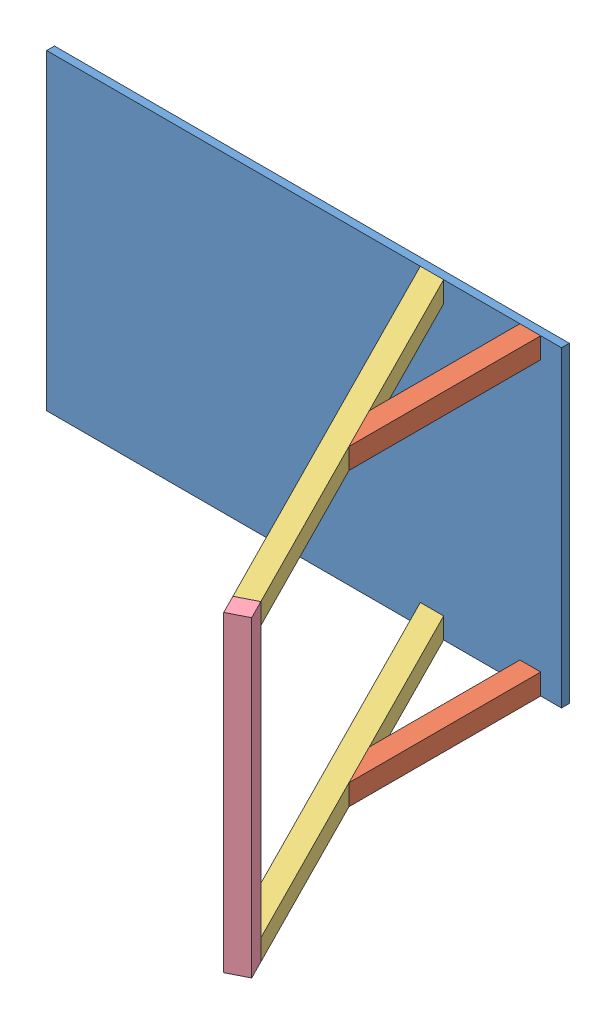
SolidWorks assembly Full_Assembly, configuration Default. Lengths in mm.
Overall size (6076.28 3048 4080.32).
6 component instances, 4 part files, 16 mates.
Components (placement in the parent):
- Boat_Deck-3: Boat_Deck [Default] at origin size (5029.2 3048 76.2)
- Vertical_Rod-1: Vertical_Rod [Default] at (4622.8 203.2 76.2) x (1 0 0) z (0 -1 0) size (203.2 1873.5 203.2)
- Vertical_Rod-2: Vertical_Rod [Default] at (4622.8 3048 76.2) x (1 0 0) z (0 -1 0) size (203.2 1873.5 203.2)
- Angled_Rod-2: Angled_Rod [Default] at (3649.8183 3048 76.2) x (0.451656 0 0.892192) z (0.892192 0 -0.451656) size (4155.69 203.2 203.2)
- Angled_Rod-3: Angled_Rod [Default] at (3649.8183 203.2 76.2) x (0.451656 0 0.892192) z (0.892192 0 -0.451656) size (4155.69 203.2 203.2)
- ME_526 final project cross bar-1: ME_526 final project cross bar [Default] at (5526.7637 0 3783.877) x (0.892192 0 -0.451656) z (0 -1 0) size (203.2 203.2 3048)
Mates (geometry in assembly coordinates):
- Parallel1: parallel anti-aligned: plane of Boat_Deck-3 through (0 0 76.2) normal (0 0 1); plane of Vertical_Rod-1 through (4622.8 0 76.2) normal (0 0 -1)
- Distance1: distance = 203.2 mm aligned: plane of Vertical_Rod-1 through (4826 0 76.2) normal (1 0 0); plane of Boat_Deck-3 through (5029.2 0 76.2) normal (1 0 0)
- Coincident1: coincident aligned: line of Boat_Deck-3 through (0 0 76.2) axis (1 0 0); line of Vertical_Rod-1 through (4622.8 0 76.2) axis (1 0 0)
- Parallel2: parallel anti-aligned: plane of Boat_Deck-3 through (0 0 76.2) normal (0 0 1); plane of Vertical_Rod-2 through (4622.8 2844.8 76.2) normal (0 0 -1)
- Distance2: distance = 203.2 mm aligned: plane of Vertical_Rod-2 through (4826 2844.8 76.2) normal (1 0 0); plane of Boat_Deck-3 through (5029.2 0 76.2) normal (1 0 0)
- Coincident2: coincident aligned: plane of Boat_Deck-3 through (0 3048 76.2) normal (0 1 0); plane of Vertical_Rod-2 through (4622.8 3048 76.2) normal (0 1 0)
- Coincident3: coincident anti-aligned: plane of Boat_Deck-3 through (0 0 76.2) normal (0 0 1); plane of Vertical_Rod-2 through (4622.8 2844.8 76.2) normal (0 0 -1)
- Parallel4: parallel anti-aligned: plane of Boat_Deck-3 through (0 0 76.2) normal (0 0 1); plane of Angled_Rod-2 through (3649.8183 3048 76.2) normal (0 0 -1)
- Coincident7: coincident aligned: line of Vertical_Rod-2 through (4826 2844.8 1949.704) axis (-0.451656 0 -0.892192); line of Angled_Rod-2 through (5708.0571 2844.8 3692.1004) axis (-0.451656 0 -0.892192)
- Coincident8: coincident aligned: line of Boat_Deck-3 through (5029.2 3048 76.2) axis (-1 0 0); line of Angled_Rod-2 through (3877.572 3048 76.2) axis (-1 0 0)
- Parallel5: parallel anti-aligned: plane of Boat_Deck-3 through (0 0 76.2) normal (0 0 1); plane of Angled_Rod-3 through (3649.8183 203.2 76.2) normal (0 0 -1)
- Coincident9: coincident aligned: line of Vertical_Rod-1 through (4826 0 1949.704) axis (-0.451656 0 -0.892192); line of Angled_Rod-3 through (5708.0571 0 3692.1004) axis (-0.451656 0 -0.892192)
- Coincident10: coincident aligned: line of Boat_Deck-3 through (0 0 76.2) axis (1 0 0); line of Angled_Rod-3 through (3649.8183 0 76.2) axis (1 0 0)
- Coincident11: coincident: point of Angled_Rod-3; point of ME_526 final project cross bar-1
- Coincident12: coincident: point of Angled_Rod-3; point of ME_526 final project cross bar-1
- Parallel6: parallel aligned: plane of Angled_Rod-3 through (3831.1118 0 -15.5766) normal (0 -1 0); plane of ME_526 final project cross bar-1 through (5526.7637 0 3783.877) normal (0 -1 0)
